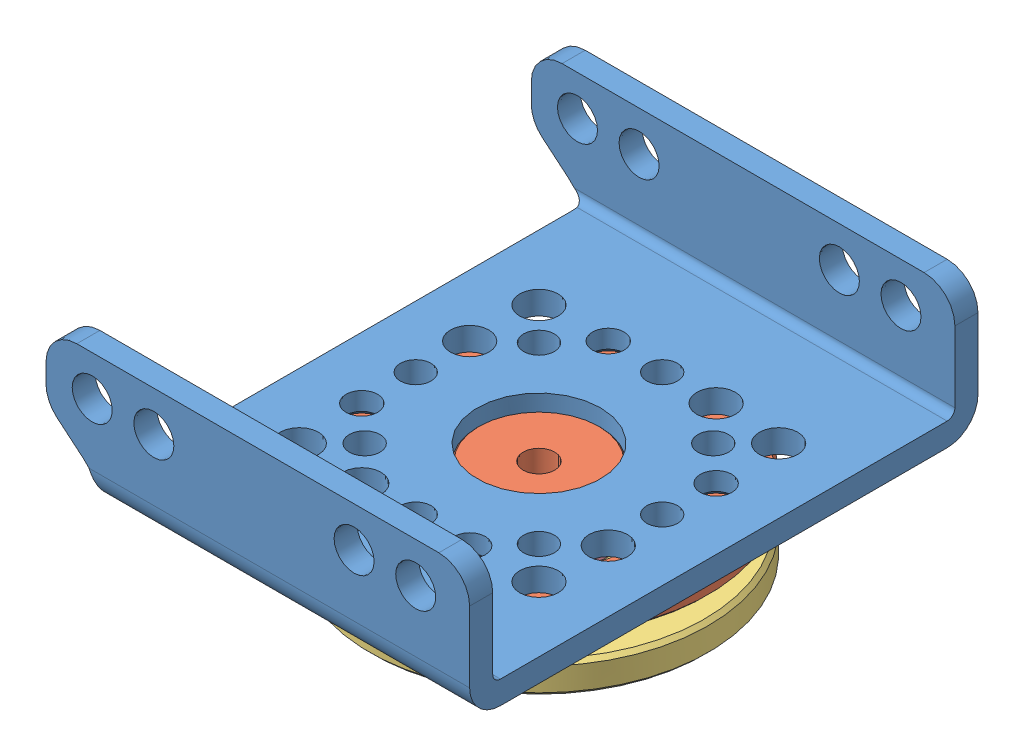
SolidWorks assembly FR07-F101K Set, configuration Défaut. Lengths in mm.
Overall size (30.73 14.25 33.02).
5 component instances, 5 part files, 9 mates.
Components (placement in the parent):
- FR07-S101-1: FR07-S101 [Défaut] at (-54.7165 7.9231 0) size (27.5 8.61 33.02)
- FR07-F101-1: FR07-F101 [Défaut] at (-54.7165 7.9231 0) x (1 0 0) z (0 -1 0) size (22 22 4.25)
- HN07-i101-1: HN07-i101 [Défaut] at (-54.7165 2.9231 0) x (-0.837169 0 -0.546944) z (-0.546944 0 0.837169) size (22 3.05 22)
- MF106ZZ-1: MF106ZZ [Défaut] at (-54.7165 3.0731 0) x (0.999998 0 0.002201) z (-0.002201 0 0.999998) size (11.2 3 11.2)
- RX28-CAP-1: RX28-CAP [Défaut] at (-54.7165 3.0731 0) x (0.935114 0 -0.354346) z (0 -1 0) size (7.2 7.2 1.8)
Mates (geometry in assembly coordinates):
- Concentric1: concentric aligned: cylinder of FR07-S101-1 through (-54.7165 8.6731 0) axis (0 -1 0) radius 4; cylinder of FR07-F101-1 through (-54.7165 8.6356 0) axis (0 -1 0) radius 4
- Coincident1: coincident anti-aligned: plane of FR07-S101-1 through (-42.7165 7.9231 14.5) normal (0 -1 0); plane of FR07-F101-1 through (-54.7165 7.9231 0) normal (0 1 0)
- Concentric2: concentric anti-aligned: cylinder of FR07-S101-1 through (-46.7165 9.4231 0) axis (0 -1 0) radius 1; cylinder of FR07-F101-1 through (-46.7165 3.5393 0) axis (0 1 0) radius 0.8
- Concentric3: concentric aligned: cylinder of FR07-F101-1 through (-54.7165 8.6356 0) axis (0 -1 0) radius 3; cylinder of HN07-i101-1 through (-54.7165 2.9231 0) axis (0 -1 0) radius 5
- Concentric4: concentric anti-aligned: cylinder of HN07-i101-1 through (-54.7165 2.9231 0) axis (0 -1 0) radius 5; cylinder of MF106ZZ-1 through (-54.7165 3.0731 0) axis (0 1 0) radius 5
- Coincident2: coincident anti-aligned: plane of HN07-i101-1 through (-58.9024 3.6731 -2.7347) normal (0 -1 0); plane of MF106ZZ-1 through (-49.7165 3.6731 0.011) normal (0 1 0)
- Concentric5: concentric anti-aligned: cylinder of MF106ZZ-1 through (-54.7165 3.0731 0) axis (0 1 0) radius 3; cylinder of RX28-CAP-1 through (-54.7165 4.0731 0) axis (0 -1 0) radius 3
- Coincident3: coincident anti-aligned: plane of MF106ZZ-1 through (-49.1165 3.0731 0.0123) normal (0 -1 0); plane of RX28-CAP-1 through (-51.4436 3.0731 -1.2402) normal (0 1 0)
- Coincident4: coincident anti-aligned: plane of FR07-F101-1 through (-54.7165 6.0731 0) normal (0 -1 0); plane of MF106ZZ-1 through (-51.7165 6.0731 0.0066) normal (0 1 0)
